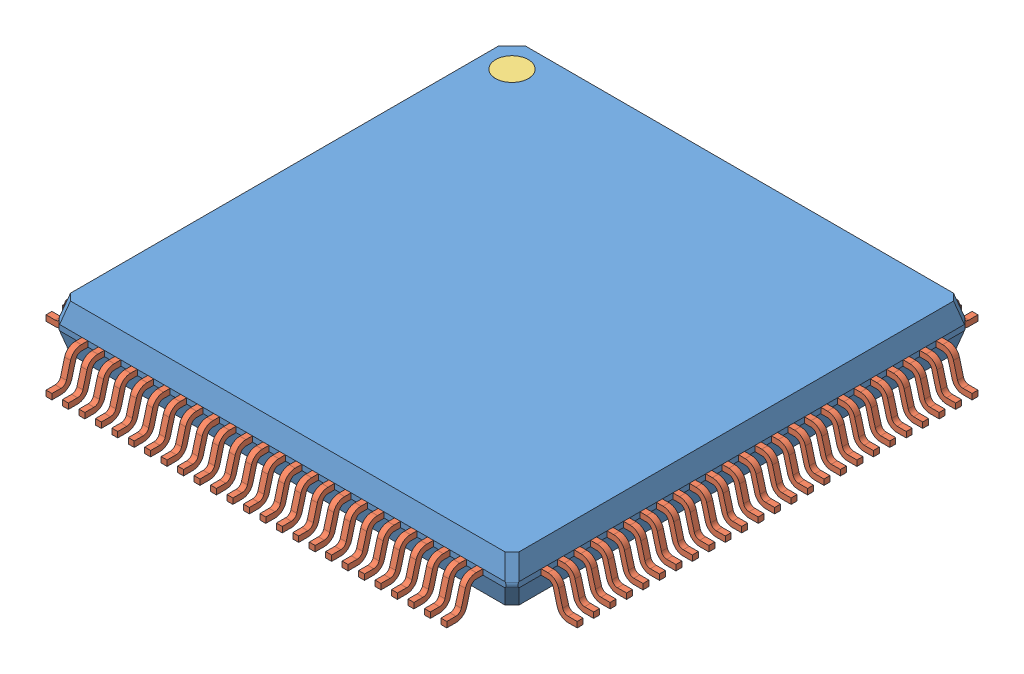
SolidWorks assembly User Library-LQFP100-3, configuration Default. Lengths in mm.
Overall size (16.14 1.63 16.14).
102 component instances, 3 part files, 0 mates.
Components (placement in the parent):
- User Library-LQFP100-3_case-1: User Library-LQFP100-3_case [Default] at (0 0.92 0) size (13.96 1.4 13.96)
- User Library-LQFP100-3_pin-1: User Library-LQFP100-3_pin [Default] at (-6 0.8321 6.978) size (0.18 1.01 1.09)
- User Library-LQFP100-3_pin-26: User Library-LQFP100-3_pin [Default] at (6.978 0.8321 6) x (0 0 -1) z (1 0 0) size (0.18 1.01 1.09)
- User Library-LQFP100-3_circle-1: User Library-LQFP100-3_circle [Default] at (-6 1.52 -6) size (1 0.1 1)
- User Library-LQFP100-3_pin-101: User Library-LQFP100-3_pin [Default] at (-5.5 0.8321 6.978) size (0.18 1.01 1.09)
- User Library-LQFP100-3_pin-102: User Library-LQFP100-3_pin [Default] at (-5 0.8321 6.978) size (0.18 1.01 1.09)
- User Library-LQFP100-3_pin-103: User Library-LQFP100-3_pin [Default] at (-4.5 0.8321 6.978) size (0.18 1.01 1.09)
- User Library-LQFP100-3_pin-104: User Library-LQFP100-3_pin [Default] at (-4 0.8321 6.978) size (0.18 1.01 1.09)
- User Library-LQFP100-3_pin-105: User Library-LQFP100-3_pin [Default] at (-3.5 0.8321 6.978) size (0.18 1.01 1.09)
- User Library-LQFP100-3_pin-106: User Library-LQFP100-3_pin [Default] at (-3 0.8321 6.978) size (0.18 1.01 1.09)
- User Library-LQFP100-3_pin-107: User Library-LQFP100-3_pin [Default] at (-2.5 0.8321 6.978) size (0.18 1.01 1.09)
- User Library-LQFP100-3_pin-108: User Library-LQFP100-3_pin [Default] at (-2 0.8321 6.978) size (0.18 1.01 1.09)
- User Library-LQFP100-3_pin-109: User Library-LQFP100-3_pin [Default] at (-1.5 0.8321 6.978) size (0.18 1.01 1.09)
- User Library-LQFP100-3_pin-110: User Library-LQFP100-3_pin [Default] at (-1 0.8321 6.978) size (0.18 1.01 1.09)
- User Library-LQFP100-3_pin-111: User Library-LQFP100-3_pin [Default] at (-0.5 0.8321 6.978) size (0.18 1.01 1.09)
- User Library-LQFP100-3_pin-112: User Library-LQFP100-3_pin [Default] at (0 0.8321 6.978) size (0.18 1.01 1.09)
- User Library-LQFP100-3_pin-113: User Library-LQFP100-3_pin [Default] at (0.5 0.8321 6.978) size (0.18 1.01 1.09)
- User Library-LQFP100-3_pin-114: User Library-LQFP100-3_pin [Default] at (1 0.8321 6.978) size (0.18 1.01 1.09)
- User Library-LQFP100-3_pin-115: User Library-LQFP100-3_pin [Default] at (1.5 0.8321 6.978) size (0.18 1.01 1.09)
- User Library-LQFP100-3_pin-116: User Library-LQFP100-3_pin [Default] at (2 0.8321 6.978) size (0.18 1.01 1.09)
- User Library-LQFP100-3_pin-117: User Library-LQFP100-3_pin [Default] at (2.5 0.8321 6.978) size (0.18 1.01 1.09)
- User Library-LQFP100-3_pin-118: User Library-LQFP100-3_pin [Default] at (3 0.8321 6.978) size (0.18 1.01 1.09)
- User Library-LQFP100-3_pin-119: User Library-LQFP100-3_pin [Default] at (3.5 0.8321 6.978) size (0.18 1.01 1.09)
- User Library-LQFP100-3_pin-120: User Library-LQFP100-3_pin [Default] at (4 0.8321 6.978) size (0.18 1.01 1.09)
- User Library-LQFP100-3_pin-121: User Library-LQFP100-3_pin [Default] at (4.5 0.8321 6.978) size (0.18 1.01 1.09)
- User Library-LQFP100-3_pin-122: User Library-LQFP100-3_pin [Default] at (5 0.8321 6.978) size (0.18 1.01 1.09)
- User Library-LQFP100-3_pin-123: User Library-LQFP100-3_pin [Default] at (5.5 0.8321 6.978) size (0.18 1.01 1.09)
- User Library-LQFP100-3_pin-124: User Library-LQFP100-3_pin [Default] at (6 0.8321 6.978) size (0.18 1.01 1.09)
- User Library-LQFP100-3_pin-125: User Library-LQFP100-3_pin [Default] at (6.978 0.8321 5.5) x (0 0 -1) z (1 0 0) size (0.18 1.01 1.09)
- User Library-LQFP100-3_pin-126: User Library-LQFP100-3_pin [Default] at (6.978 0.8321 5) x (0 0 -1) z (1 0 0) size (0.18 1.01 1.09)
- User Library-LQFP100-3_pin-127: User Library-LQFP100-3_pin [Default] at (6.978 0.8321 4.5) x (0 0 -1) z (1 0 0) size (0.18 1.01 1.09)
- User Library-LQFP100-3_pin-128: User Library-LQFP100-3_pin [Default] at (6.978 0.8321 4) x (0 0 -1) z (1 0 0) size (0.18 1.01 1.09)
- User Library-LQFP100-3_pin-129: User Library-LQFP100-3_pin [Default] at (6.978 0.8321 3.5) x (0 0 -1) z (1 0 0) size (0.18 1.01 1.09)
- User Library-LQFP100-3_pin-130: User Library-LQFP100-3_pin [Default] at (6.978 0.8321 3) x (0 0 -1) z (1 0 0) size (0.18 1.01 1.09)
- User Library-LQFP100-3_pin-131: User Library-LQFP100-3_pin [Default] at (6.978 0.8321 2.5) x (0 0 -1) z (1 0 0) size (0.18 1.01 1.09)
- User Library-LQFP100-3_pin-132: User Library-LQFP100-3_pin [Default] at (6.978 0.8321 2) x (0 0 -1) z (1 0 0) size (0.18 1.01 1.09)
- User Library-LQFP100-3_pin-133: User Library-LQFP100-3_pin [Default] at (6.978 0.8321 1.5) x (0 0 -1) z (1 0 0) size (0.18 1.01 1.09)
- User Library-LQFP100-3_pin-134: User Library-LQFP100-3_pin [Default] at (6.978 0.8321 1) x (0 0 -1) z (1 0 0) size (0.18 1.01 1.09)
- User Library-LQFP100-3_pin-135: User Library-LQFP100-3_pin [Default] at (6.978 0.8321 0.5) x (0 0 -1) z (1 0 0) size (0.18 1.01 1.09)
- User Library-LQFP100-3_pin-136: User Library-LQFP100-3_pin [Default] at (6.978 0.8321 0) x (0 0 -1) z (1 0 0) size (0.18 1.01 1.09)
- User Library-LQFP100-3_pin-137: User Library-LQFP100-3_pin [Default] at (6.978 0.8321 -0.5) x (0 0 -1) z (1 0 0) size (0.18 1.01 1.09)
- User Library-LQFP100-3_pin-138: User Library-LQFP100-3_pin [Default] at (6.978 0.8321 -1) x (0 0 -1) z (1 0 0) size (0.18 1.01 1.09)
- User Library-LQFP100-3_pin-139: User Library-LQFP100-3_pin [Default] at (6.978 0.8321 -1.5) x (0 0 -1) z (1 0 0) size (0.18 1.01 1.09)
- User Library-LQFP100-3_pin-140: User Library-LQFP100-3_pin [Default] at (6.978 0.8321 -2) x (0 0 -1) z (1 0 0) size (0.18 1.01 1.09)
- User Library-LQFP100-3_pin-141: User Library-LQFP100-3_pin [Default] at (6.978 0.8321 -2.5) x (0 0 -1) z (1 0 0) size (0.18 1.01 1.09)
- User Library-LQFP100-3_pin-142: User Library-LQFP100-3_pin [Default] at (6.978 0.8321 -3) x (0 0 -1) z (1 0 0) size (0.18 1.01 1.09)
- User Library-LQFP100-3_pin-143: User Library-LQFP100-3_pin [Default] at (6.978 0.8321 -3.5) x (0 0 -1) z (1 0 0) size (0.18 1.01 1.09)
- User Library-LQFP100-3_pin-144: User Library-LQFP100-3_pin [Default] at (6.978 0.8321 -4) x (0 0 -1) z (1 0 0) size (0.18 1.01 1.09)
- User Library-LQFP100-3_pin-145: User Library-LQFP100-3_pin [Default] at (6.978 0.8321 -4.5) x (0 0 -1) z (1 0 0) size (0.18 1.01 1.09)
- User Library-LQFP100-3_pin-146: User Library-LQFP100-3_pin [Default] at (6.978 0.8321 -5) x (0 0 -1) z (1 0 0) size (0.18 1.01 1.09)
- User Library-LQFP100-3_pin-147: User Library-LQFP100-3_pin [Default] at (6.978 0.8321 -5.5) x (0 0 -1) z (1 0 0) size (0.18 1.01 1.09)
- User Library-LQFP100-3_pin-148: User Library-LQFP100-3_pin [Default] at (6.978 0.8321 -6) x (0 0 -1) z (1 0 0) size (0.18 1.01 1.09)
- User Library-LQFP100-3_pin-149: User Library-LQFP100-3_pin [Default] at (-6 0.8321 -6.978) x (-1 0 0) z (0 0 -1) size (0.18 1.01 1.09)
- User Library-LQFP100-3_pin-150: User Library-LQFP100-3_pin [Default] at (-5.5 0.8321 -6.978) x (-1 0 0) z (0 0 -1) size (0.18 1.01 1.09)
- User Library-LQFP100-3_pin-151: User Library-LQFP100-3_pin [Default] at (-5 0.8321 -6.978) x (-1 0 0) z (0 0 -1) size (0.18 1.01 1.09)
- User Library-LQFP100-3_pin-152: User Library-LQFP100-3_pin [Default] at (-4.5 0.8321 -6.978) x (-1 0 0) z (0 0 -1) size (0.18 1.01 1.09)
- User Library-LQFP100-3_pin-153: User Library-LQFP100-3_pin [Default] at (-4 0.8321 -6.978) x (-1 0 0) z (0 0 -1) size (0.18 1.01 1.09)
- User Library-LQFP100-3_pin-154: User Library-LQFP100-3_pin [Default] at (-3.5 0.8321 -6.978) x (-1 0 0) z (0 0 -1) size (0.18 1.01 1.09)
- User Library-LQFP100-3_pin-155: User Library-LQFP100-3_pin [Default] at (-3 0.8321 -6.978) x (-1 0 0) z (0 0 -1) size (0.18 1.01 1.09)
- User Library-LQFP100-3_pin-156: User Library-LQFP100-3_pin [Default] at (-2.5 0.8321 -6.978) x (-1 0 0) z (0 0 -1) size (0.18 1.01 1.09)
- User Library-LQFP100-3_pin-157: User Library-LQFP100-3_pin [Default] at (-2 0.8321 -6.978) x (-1 0 0) z (0 0 -1) size (0.18 1.01 1.09)
- User Library-LQFP100-3_pin-158: User Library-LQFP100-3_pin [Default] at (-1.5 0.8321 -6.978) x (-1 0 0) z (0 0 -1) size (0.18 1.01 1.09)
- User Library-LQFP100-3_pin-159: User Library-LQFP100-3_pin [Default] at (-1 0.8321 -6.978) x (-1 0 0) z (0 0 -1) size (0.18 1.01 1.09)
- User Library-LQFP100-3_pin-160: User Library-LQFP100-3_pin [Default] at (-0.5 0.8321 -6.978) x (-1 0 0) z (0 0 -1) size (0.18 1.01 1.09)
- User Library-LQFP100-3_pin-161: User Library-LQFP100-3_pin [Default] at (0 0.8321 -6.978) x (-1 0 0) z (0 0 -1) size (0.18 1.01 1.09)
- User Library-LQFP100-3_pin-162: User Library-LQFP100-3_pin [Default] at (0.5 0.8321 -6.978) x (-1 0 0) z (0 0 -1) size (0.18 1.01 1.09)
- User Library-LQFP100-3_pin-163: User Library-LQFP100-3_pin [Default] at (1 0.8321 -6.978) x (-1 0 0) z (0 0 -1) size (0.18 1.01 1.09)
- User Library-LQFP100-3_pin-164: User Library-LQFP100-3_pin [Default] at (1.5 0.8321 -6.978) x (-1 0 0) z (0 0 -1) size (0.18 1.01 1.09)
- User Library-LQFP100-3_pin-165: User Library-LQFP100-3_pin [Default] at (2 0.8321 -6.978) x (-1 0 0) z (0 0 -1) size (0.18 1.01 1.09)
- User Library-LQFP100-3_pin-166: User Library-LQFP100-3_pin [Default] at (2.5 0.8321 -6.978) x (-1 0 0) z (0 0 -1) size (0.18 1.01 1.09)
- User Library-LQFP100-3_pin-167: User Library-LQFP100-3_pin [Default] at (3 0.8321 -6.978) x (-1 0 0) z (0 0 -1) size (0.18 1.01 1.09)
- User Library-LQFP100-3_pin-168: User Library-LQFP100-3_pin [Default] at (3.5 0.8321 -6.978) x (-1 0 0) z (0 0 -1) size (0.18 1.01 1.09)
- User Library-LQFP100-3_pin-169: User Library-LQFP100-3_pin [Default] at (4 0.8321 -6.978) x (-1 0 0) z (0 0 -1) size (0.18 1.01 1.09)
- User Library-LQFP100-3_pin-170: User Library-LQFP100-3_pin [Default] at (4.5 0.8321 -6.978) x (-1 0 0) z (0 0 -1) size (0.18 1.01 1.09)
- User Library-LQFP100-3_pin-171: User Library-LQFP100-3_pin [Default] at (5 0.8321 -6.978) x (-1 0 0) z (0 0 -1) size (0.18 1.01 1.09)
- User Library-LQFP100-3_pin-172: User Library-LQFP100-3_pin [Default] at (5.5 0.8321 -6.978) x (-1 0 0) z (0 0 -1) size (0.18 1.01 1.09)
- User Library-LQFP100-3_pin-173: User Library-LQFP100-3_pin [Default] at (6 0.8321 -6.978) x (-1 0 0) z (0 0 -1) size (0.18 1.01 1.09)
- User Library-LQFP100-3_pin-174: User Library-LQFP100-3_pin [Default] at (-6.978 0.8321 6) x (0 0 1) z (-1 0 0) size (0.18 1.01 1.09)
- User Library-LQFP100-3_pin-175: User Library-LQFP100-3_pin [Default] at (-6.978 0.8321 5.5) x (0 0 1) z (-1 0 0) size (0.18 1.01 1.09)
- User Library-LQFP100-3_pin-176: User Library-LQFP100-3_pin [Default] at (-6.978 0.8321 5) x (0 0 1) z (-1 0 0) size (0.18 1.01 1.09)
- User Library-LQFP100-3_pin-177: User Library-LQFP100-3_pin [Default] at (-6.978 0.8321 4.5) x (0 0 1) z (-1 0 0) size (0.18 1.01 1.09)
- User Library-LQFP100-3_pin-178: User Library-LQFP100-3_pin [Default] at (-6.978 0.8321 4) x (0 0 1) z (-1 0 0) size (0.18 1.01 1.09)
- User Library-LQFP100-3_pin-179: User Library-LQFP100-3_pin [Default] at (-6.978 0.8321 3.5) x (0 0 1) z (-1 0 0) size (0.18 1.01 1.09)
- User Library-LQFP100-3_pin-180: User Library-LQFP100-3_pin [Default] at (-6.978 0.8321 3) x (0 0 1) z (-1 0 0) size (0.18 1.01 1.09)
- User Library-LQFP100-3_pin-181: User Library-LQFP100-3_pin [Default] at (-6.978 0.8321 2.5) x (0 0 1) z (-1 0 0) size (0.18 1.01 1.09)
- User Library-LQFP100-3_pin-182: User Library-LQFP100-3_pin [Default] at (-6.978 0.8321 2) x (0 0 1) z (-1 0 0) size (0.18 1.01 1.09)
- User Library-LQFP100-3_pin-183: User Library-LQFP100-3_pin [Default] at (-6.978 0.8321 1.5) x (0 0 1) z (-1 0 0) size (0.18 1.01 1.09)
- User Library-LQFP100-3_pin-184: User Library-LQFP100-3_pin [Default] at (-6.978 0.8321 1) x (0 0 1) z (-1 0 0) size (0.18 1.01 1.09)
- User Library-LQFP100-3_pin-185: User Library-LQFP100-3_pin [Default] at (-6.978 0.8321 0.5) x (0 0 1) z (-1 0 0) size (0.18 1.01 1.09)
- User Library-LQFP100-3_pin-186: User Library-LQFP100-3_pin [Default] at (-6.978 0.8321 0) x (0 0 1) z (-1 0 0) size (0.18 1.01 1.09)
- User Library-LQFP100-3_pin-187: User Library-LQFP100-3_pin [Default] at (-6.978 0.8321 -0.5) x (0 0 1) z (-1 0 0) size (0.18 1.01 1.09)
- User Library-LQFP100-3_pin-188: User Library-LQFP100-3_pin [Default] at (-6.978 0.8321 -1) x (0 0 1) z (-1 0 0) size (0.18 1.01 1.09)
- User Library-LQFP100-3_pin-189: User Library-LQFP100-3_pin [Default] at (-6.978 0.8321 -1.5) x (0 0 1) z (-1 0 0) size (0.18 1.01 1.09)
- User Library-LQFP100-3_pin-190: User Library-LQFP100-3_pin [Default] at (-6.978 0.8321 -2) x (0 0 1) z (-1 0 0) size (0.18 1.01 1.09)
- User Library-LQFP100-3_pin-191: User Library-LQFP100-3_pin [Default] at (-6.978 0.8321 -2.5) x (0 0 1) z (-1 0 0) size (0.18 1.01 1.09)
- User Library-LQFP100-3_pin-192: User Library-LQFP100-3_pin [Default] at (-6.978 0.8321 -3) x (0 0 1) z (-1 0 0) size (0.18 1.01 1.09)
- User Library-LQFP100-3_pin-193: User Library-LQFP100-3_pin [Default] at (-6.978 0.8321 -3.5) x (0 0 1) z (-1 0 0) size (0.18 1.01 1.09)
- User Library-LQFP100-3_pin-194: User Library-LQFP100-3_pin [Default] at (-6.978 0.8321 -4) x (0 0 1) z (-1 0 0) size (0.18 1.01 1.09)
- User Library-LQFP100-3_pin-195: User Library-LQFP100-3_pin [Default] at (-6.978 0.8321 -4.5) x (0 0 1) z (-1 0 0) size (0.18 1.01 1.09)
- User Library-LQFP100-3_pin-196: User Library-LQFP100-3_pin [Default] at (-6.978 0.8321 -5) x (0 0 1) z (-1 0 0) size (0.18 1.01 1.09)
- User Library-LQFP100-3_pin-197: User Library-LQFP100-3_pin [Default] at (-6.978 0.8321 -5.5) x (0 0 1) z (-1 0 0) size (0.18 1.01 1.09)
- User Library-LQFP100-3_pin-198: User Library-LQFP100-3_pin [Default] at (-6.978 0.8321 -6) x (0 0 1) z (-1 0 0) size (0.18 1.01 1.09)
